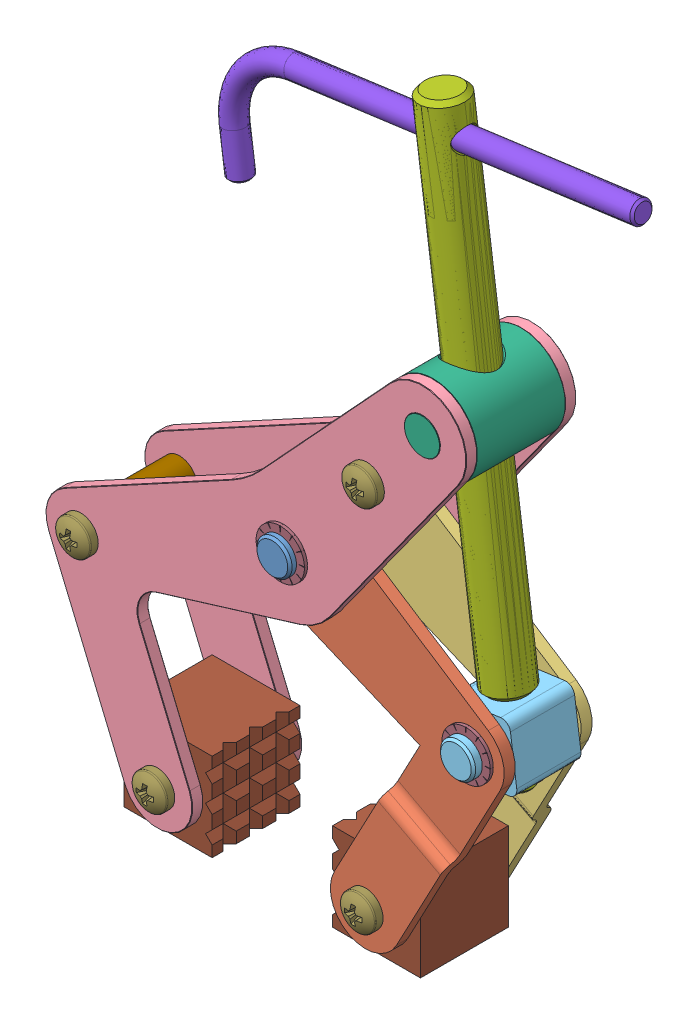
SolidWorks assembly Manual Clamp Assembly, configuration Default. Lengths in mm.
Overall size (140.09 169.84 31.04).
28 component instances, 13 part files, 60 mates.
Components (placement in the parent):
- Clamp hinge-1: Clamp hinge [Default] at origin size (18 18 30)
- Clamp elbow left-1: Clamp elbow left [Default] at (52.873 3.6662 7.5) x (0.468304 0.883567 0) z (0.883567 -0.468304 0) size (65 5 65)
- Clamp elbow right-1: Clamp elbow right [Default] at (43.507 -14.0051 -7.5) x (-0.468304 -0.883567 0) z (0.883567 -0.468304 0) size (65 5 65)
- Clamp Base-1: Clamp Base [Default] at (0 0 11.25) x (-0.598314 0.801262 0) z (-0.801262 -0.598314 0) size (61.66 2.5 125.92)
- Clamp Base-2: Clamp Base [Default] at (0 0 -11.25) x (-0.598314 0.801262 0) z (-0.801262 -0.598314 0) size (61.66 2.5 125.92)
- Clamp Tee-1: Clamp Tee [Default] at (32.3288 -22.0835 0) x (0 0 -1) z (0.134644 -0.990894 0) size (26 15 14.6)
- Clamp base spacer-1: Clamp base spacer [Default] at (31.6358 38.7192 0) x (0.134644 -0.990894 0) z (0 0 1) size (20 20 25.2)
- Clamp Rod-1: Clamp Rod [Default] at (23.6975 97.14 0) x (0.990894 0.134644 0.000515) z (0.134644 -0.990894 0) size (10 10 130)
- Clamp Lever-1: Clamp Lever [Default] at (69.3648 95.2718 0.0232) x (0.990894 0.134644 0.000515) z (-0.00051 -0.000069 1) size (98.5 28.5 5)
- Clamp base support-1: Clamp base support [Default] at (18.9815 23.2315 0) x (0.067715 -0.997705 0) z (0 0 1) size (8 8 24)
- Clamp base support-2: Clamp base support [Default] at (-46.1103 -19.3349 0) x (-0.069382 0.99759 0) z (0 0 1) size (8 8 24)
- Clamp Foot Pin-1: Clamp Foot Pin [Default] at (18.6868 -60.8342 0) x (0.923896 -0.382643 0) z (0 0 1) size (6 6 25)
- Clamp Foot Pin-2: Clamp Foot Pin [Default] at (-28.7088 -60.8342 0) x (0.923896 -0.382643 0) z (0 0 1) size (6 6 25)
- Clamp Foot-1: Clamp Foot [Default] at (28.6868 -60.8342 0) x (0 1 0) z (0 0 1) size (20 20 20)
- Clamp Foot-2: Clamp Foot [Default] at (-38.7088 -60.8342 0) x (0 1 0) z (0 0 -1) size (20 20 20)
- pan head cross recess screw_iso-2: pan head cross recess screw_iso [ISO 7045 - M4 x 10 - Z - 10N] at (-46.1103 -19.3349 15.6) x (0 0 -1) z (1 0 0) size (13.02 8 8)
- pan head cross recess screw_iso-3: pan head cross recess screw_iso [ISO 7045 - M4 x 10 - Z - 10N] at (-28.7088 -60.8342 15.6) x (0 0 -1) z (1 0 0) size (13.02 8 8)
- pan head cross recess screw_iso-4: pan head cross recess screw_iso [ISO 7045 - M4 x 10 - Z - 10N] at (18.6868 -60.8342 15.6) x (0 0 -1) z (1 0 0) size (13.02 8 8)
- pan head cross recess screw_iso-5: pan head cross recess screw_iso [ISO 7045 - M4 x 10 - Z - 10N] at (18.9815 23.2315 15.6) x (0 0 -1) z (1 0 0) size (13.02 8 8)
- pan head cross recess screw_iso-6: pan head cross recess screw_iso [ISO 7045 - M4 x 10 - Z - 10N] at (18.6868 -60.8342 -15.6) x (0 0 1) z (-1 0 0) size (13.02 8 8)
- pan head cross recess screw_iso-7: pan head cross recess screw_iso [ISO 7045 - M4 x 10 - Z - 10N] at (-28.7088 -60.8342 -15.6) x (0 0 1) z (-1 0 0) size (13.02 8 8)
- pan head cross recess screw_iso-8: pan head cross recess screw_iso [ISO 7045 - M4 x 10 - Z - 10N] at (-46.1103 -19.3349 -15.6) x (0 0 1) z (-1 0 0) size (13.02 8 8)
- pan head cross recess screw_iso-9: pan head cross recess screw_iso [ISO 7045 - M4 x 10 - Z - 10N] at (18.9815 23.2315 -15.6) x (0 0 1) z (-1 0 0) size (13.02 8 8)
- serrated lock washer 1_din-3: serrated lock washer 1_din [DIN 6798-A6.4] at (0 0 12.5) x (0 0 1) z (-1 0 0) size (0.7 11 11)
- serrated lock washer 1_din-5: serrated lock washer 1_din [DIN 6798-A6.4] at (0 0 -12.5) x (0 0 -1) z (1 0 0) size (0.7 11 11)
- serrated lock washer 1_din-6: serrated lock washer 1_din [DIN 6798-A6.4] at (39.7605 -21.0737 -10) x (0 0 -1) z (1 0 0) size (0.7 11 11)
- serrated lock washer 1_din-7: serrated lock washer 1_din [DIN 6798-A6.4] at (39.7605 -21.0737 10) x (0 0 1) z (-1 0 0) size (0.7 11 11)
- serrated lock washer 1_din-8: serrated lock washer 1_din [DIN 6798-A5.3] at (40.7973 -28.7036 0) x (0.134644 -0.990894 0) z (0 0 1) size (0.6 10 10)
Mates (geometry in assembly coordinates):
- Concentric1: concentric anti-aligned: cylinder of Clamp hinge-1 through (0 0 15) axis (0 0 -1) radius 4; cylinder of Clamp elbow left-1 through (0 0 7.5) axis (0 0 1) radius 4
- Coincident2: coincident anti-aligned: plane of Clamp hinge-1 through (0 0 7.5) normal (0 0 1); plane of Clamp elbow left-1 through (50.5755 -17.7516 7.5) normal (0 0 -1)
- Coincident3: coincident anti-aligned: plane of Clamp hinge-1 through (0 0 -7.5) normal (0 0 -1); plane of Clamp elbow right-1 through (50.5755 -17.7516 -7.5) normal (0 0 1)
- Concentric2: concentric anti-aligned: cylinder of Clamp hinge-1 through (0 0 -15) axis (0 0 1) radius 4; cylinder of Clamp elbow right-1 through (0 0 -7.5) axis (0 0 -1) radius 4
- Coincident4: coincident aligned: plane of Clamp elbow left-1 through (6.5399 10.0613 7.5) normal (0.54499 0.838443 0); plane of Clamp elbow right-1 through (6.5399 10.0613 -7.5) normal (0.54499 0.838443 0)
- Concentric3: concentric anti-aligned: cylinder of Clamp hinge-1 through (0 0 15) axis (0 0 -1) radius 4; cylinder of Clamp Base-1 through (0 0 10) axis (0 0 1) radius 4
- Coincident5: coincident anti-aligned: plane of Clamp elbow left-1 through (36.8776 -43.5959 10) normal (0 0 1); plane of Clamp Base-1 through (-27.2143 -28.1947 10) normal (0 0 -1)
- Concentric4: concentric aligned: cylinder of Clamp hinge-1 through (0 0 -15) axis (0 0 1) radius 4; cylinder of Clamp Base-2 through (0 0 -12.5) axis (0 0 1) radius 4
- Coincident6: coincident anti-aligned: plane of Clamp elbow right-1 through (36.8776 -43.5959 -10) normal (0 0 -1); plane of Clamp Base-2 through (-27.2143 -28.1947 -10) normal (0 0 1)
- Coincident7: coincident aligned: plane of Clamp Base-1 through (-11.8818 8.3428 10) normal (-0.476981 0.878914 0); plane of Clamp Base-2 through (-11.8818 8.3428 -12.5) normal (-0.476981 0.878914 0)
- Concentric5: concentric anti-aligned: cylinder of Clamp elbow left-1 through (39.7605 -21.0737 7.5) axis (0 0 1) radius 4; cylinder of Clamp Tee-1 through (39.7605 -21.0737 13) axis (0 0 -1) radius 4
- Concentric6: concentric anti-aligned: cylinder of Clamp Base-1 through (31.6358 38.7192 10) axis (0 0 1) radius 4; cylinder of Clamp base spacer-1 through (31.6358 38.7192 12.6) axis (0 0 -1) radius 4
- Concentric7: concentric aligned: cylinder of Clamp Tee-1 through (40.7434 -28.3072 0) axis (-0.134644 0.990894 0) radius 3; cylinder of Clamp Rod-1 through (41.2012 -31.6763 0) axis (-0.134644 0.990894 0) radius 3
- Coincident10: coincident anti-aligned: plane of Clamp Tee-1 through (46.2093 -12.8303 -7.3) normal (-0.134644 0.990894 0); plane of Clamp Rod-1 through (38.7776 -13.8402 0) normal (0.134644 -0.990894 0)
- Concentric9: concentric anti-aligned: cylinder of Clamp base spacer-1 through (30.2893 48.6282 0) axis (0.134644 -0.990894 0) radius 5; cylinder of Clamp Rod-1 through (38.7776 -13.8402 0) axis (-0.134644 0.990894 0) radius 5
- Concentric10: concentric anti-aligned: cylinder of Clamp Rod-1 through (19.8202 88.5396 -0.0026) axis (0.990894 0.134644 0.000515) radius 2.5; cylinder of Clamp Lever-1 through (69.3648 95.2718 0.0232) axis (-0.990894 -0.134644 -0.000515) radius 2.5
- Distance1: distance = 45 mm aligned: plane of Clamp Lever-1 through (69.3648 95.2718 0.0232) normal (0.990894 0.134644 0.000515); plane of Clamp Rod-1 through (23.6975 97.14 0) normal (0.990894 0.134644 0.000515)
- Parallel2: parallel anti-aligned: plane of Clamp Rod-1 through (23.6975 97.14 0) normal (-0.134644 0.990894 0); plane of Clamp Lever-1 through (-22.2602 56.5827 -0.0262) normal (0.134644 -0.990894 0)
- Concentric11: concentric aligned: cylinder of Clamp Base-2 through (18.9815 23.2315 -12.5) axis (0 0 1) radius 3; cylinder of Clamp base support-1 through (18.9815 23.2315 -12) axis (0 0 1) radius 3
- Coincident13: coincident anti-aligned: plane of Clamp Base-2 through (-27.2143 -28.1947 -10) normal (0 0 1); plane of Clamp base support-1 through (18.9815 23.2315 -10) normal (0 0 -1)
- Concentric12: concentric anti-aligned: cylinder of Clamp Base-1 through (-46.1103 -19.3349 10) axis (0 0 1) radius 3; cylinder of Clamp base support-2 through (-46.1103 -19.3349 12) axis (0 0 -1) radius 3
- Coincident14: coincident anti-aligned: plane of Clamp Base-1 through (-27.2143 -28.1947 10) normal (0 0 -1); plane of Clamp base support-2 through (-46.1103 -19.3349 10) normal (0 0 1)
- Concentric13: concentric anti-aligned: cylinder of Clamp elbow left-1 through (18.6868 -60.8342 7.5) axis (0 0 1) radius 3; cylinder of Clamp Foot Pin-1 through (18.6868 -60.8342 12.5) axis (0 0 -1) radius 3
- Coincident16: coincident aligned: plane of Clamp elbow left-1 through (22.0089 -71.6492 12.5) normal (0 0 1); plane of Clamp Foot Pin-1 through (18.6868 -60.8342 12.5) normal (0 0 1)
- Coincident18: coincident aligned: plane of Clamp elbow left-1 through (36.8776 -43.5959 10) normal (0 0 1); plane of Clamp Tee-1 through (44.4953 -20.4303 10) normal (0 0 1)
- Concentric14: concentric anti-aligned: cylinder of Clamp Base-1 through (-28.7088 -60.8342 10) axis (0 0 1) radius 3; cylinder of Clamp Foot Pin-2 through (-28.7088 -60.8342 12.5) axis (0 0 -1) radius 3
- Coincident19: coincident aligned: plane of Clamp Base-1 through (-27.2143 -28.1947 12.5) normal (0 0 1); plane of Clamp Foot Pin-2 through (-28.7088 -60.8342 12.5) normal (0 0 1)
- Concentric15: concentric anti-aligned: cylinder of Clamp Foot Pin-1 through (18.6868 -60.8342 12.5) axis (0 0 -1) radius 3; cylinder of Clamp Foot-1 through (18.6868 -60.8342 -10) axis (0 0 1) radius 3
- Coincident20: coincident anti-aligned: plane of Clamp elbow left-1 through (35.7068 -45.8048 10) normal (0 0 -1); plane of Clamp Foot-1 through (8.6868 -50.8342 10) normal (0 0 1)
- Concentric16: concentric aligned: cylinder of Clamp Foot Pin-2 through (-28.7088 -60.8342 12.5) axis (0 0 -1) radius 3; cylinder of Clamp Foot-2 through (-28.7088 -60.8342 10) axis (0 0 -1) radius 3
- Coincident21: coincident anti-aligned: plane of Clamp Base-1 through (-27.2143 -28.1947 10) normal (0 0 -1); plane of Clamp Foot-2 through (-18.7088 -50.8342 10) normal (0 0 1)
- Parallel4: parallel anti-aligned: plane of Clamp Foot-2 through (-18.7088 -70.8342 -10) normal (0 -1 0)
- Parallel5: parallel anti-aligned: plane of Clamp Foot-2 through (-18.7088 -70.8342 -10) normal (0 -1 0)
- Coincident25: coincident aligned: plane of Clamp Foot-1 through (8.6868 -70.8342 10) normal (0 -1 0); plane of Clamp Foot-2 through (-18.7088 -70.8342 -10) normal (0 -1 0)
- Concentric17: concentric anti-aligned: cone of Clamp Base-1 through (-46.1103 -19.3349 12.5) axis (0 0 -1); cylinder of pan head cross recess screw_iso-2 through (-46.1103 -19.3349 41) axis (0 0 1) radius 4
- Coincident26: coincident anti-aligned: plane of Clamp Base-1 through (-27.2143 -28.1947 12.5) normal (0 0 1); plane of pan head cross recess screw_iso-2 through (-46.1103 -17.3349 12.5) normal (0 0 -1)
- Concentric18: concentric anti-aligned: cone of Clamp Base-1 through (-28.7088 -60.8342 12.5) axis (0 0 -1); cylinder of pan head cross recess screw_iso-3 through (-28.7088 -60.8342 41) axis (0 0 1) radius 4
- Coincident27: coincident anti-aligned: plane of Clamp Base-1 through (-27.2143 -28.1947 12.5) normal (0 0 1); plane of pan head cross recess screw_iso-3 through (-28.7088 -58.8342 12.5) normal (0 0 -1)
- Concentric19: concentric anti-aligned: cylinder of Clamp elbow left-1 through (18.6868 -60.8342 7.5) axis (0 0 -1) radius 8; cylinder of pan head cross recess screw_iso-4 through (18.6868 -60.8342 41) axis (0 0 1) radius 4
- Coincident28: coincident anti-aligned: plane of Clamp elbow left-1 through (22.0089 -71.6492 12.5) normal (0 0 1); plane of pan head cross recess screw_iso-4 through (18.6868 -58.8342 12.5) normal (0 0 -1)
- Concentric20: concentric anti-aligned: cone of Clamp Base-1 through (18.9815 23.2315 12.5) axis (0 0 -1); cylinder of pan head cross recess screw_iso-5 through (18.9815 23.2315 41) axis (0 0 1) radius 4
- Coincident29: coincident anti-aligned: plane of Clamp Base-1 through (-27.2143 -28.1947 12.5) normal (0 0 1); plane of pan head cross recess screw_iso-5 through (18.9815 25.2315 12.5) normal (0 0 -1)
- Concentric21: concentric anti-aligned: cylinder of Clamp elbow right-1 through (18.6868 -60.8342 -7.5) axis (0 0 1) radius 8; cylinder of pan head cross recess screw_iso-6 through (18.6868 -60.8342 -41) axis (0 0 -1) radius 4
- Coincident30: coincident anti-aligned: plane of Clamp elbow right-1 through (22.0089 -71.6492 -12.5) normal (0 0 -1); plane of pan head cross recess screw_iso-6 through (18.6868 -58.8342 -12.5) normal (0 0 1)
- Concentric22: concentric aligned: cone of Clamp Base-2 through (-28.7088 -60.8342 -12.5) axis (0 0 -1); cylinder of pan head cross recess screw_iso-7 through (-28.7088 -60.8342 -41) axis (0 0 -1) radius 4
- Coincident31: coincident anti-aligned: plane of Clamp Base-2 through (-27.2143 -28.1947 -12.5) normal (0 0 -1); plane of pan head cross recess screw_iso-7 through (-28.7088 -58.8342 -12.5) normal (0 0 1)
- Concentric23: concentric anti-aligned: cone of Clamp Base-2 through (-46.1103 -19.3349 -12.4) axis (0 0 1); cylinder of pan head cross recess screw_iso-8 through (-46.1103 -19.3349 -41) axis (0 0 -1) radius 4
- Coincident32: coincident anti-aligned: plane of Clamp Base-2 through (-27.2143 -28.1947 -12.5) normal (0 0 -1); plane of pan head cross recess screw_iso-8 through (-46.1103 -17.3349 -12.5) normal (0 0 1)
- Concentric24: concentric anti-aligned: cone of Clamp Base-2 through (18.9815 23.2315 -12.4) axis (0 0 1); cylinder of pan head cross recess screw_iso-9 through (18.9815 23.2315 -41) axis (0 0 -1) radius 4
- Coincident33: coincident anti-aligned: plane of Clamp Base-2 through (-27.2143 -28.1947 -12.5) normal (0 0 -1); plane of pan head cross recess screw_iso-9 through (18.9815 25.2315 -12.5) normal (0 0 1)
- Concentric26: concentric anti-aligned: cylinder of Clamp hinge-1 through (0 0 15) axis (0 0 1) radius 3; cylinder of serrated lock washer 1_din-3 through (0 0 13.2) axis (0 0 -1) radius 5.5
- Coincident35: coincident anti-aligned: plane of Clamp hinge-1 through (0 4.614 12.5) normal (0 0 1); plane of serrated lock washer 1_din-3 through (0 0 12.5) normal (0 0 -1)
- Concentric28: concentric anti-aligned: cylinder of Clamp hinge-1 through (0 0 -15) axis (0 0 -1) radius 3; cylinder of serrated lock washer 1_din-5 through (0 0 -13.2) axis (0 0 1) radius 5.5
- Coincident37: coincident anti-aligned: plane of Clamp hinge-1 through (0 4.614 -12.5) normal (0 0 -1); plane of serrated lock washer 1_din-5 through (0 0 -12.5) normal (0 0 1)
- Concentric29: concentric anti-aligned: cylinder of Clamp elbow right-1 through (39.7605 -21.0737 -7.5) axis (0 0 -1) radius 4; cylinder of serrated lock washer 1_din-6 through (39.7605 -21.0737 -10.7) axis (0 0 1) radius 5.5
- Coincident38: coincident anti-aligned: plane of Clamp elbow right-1 through (36.8776 -43.5959 -10) normal (0 0 -1); plane of serrated lock washer 1_din-6 through (39.7605 -21.0737 -10) normal (0 0 1)
- Concentric301: concentric anti-aligned: cylinder of Clamp elbow left-1 through (39.7605 -21.0737 7.5) axis (0 0 1) radius 4; cylinder of serrated lock washer 1_din-7 through (39.7605 -21.0737 10.7) axis (0 0 -1) radius 5.5
- Coincident391: coincident anti-aligned: plane of Clamp elbow left-1 through (36.8776 -43.5959 10) normal (0 0 1); plane of serrated lock washer 1_din-7 through (39.7605 -21.0737 10) normal (0 0 -1)
- Concentric31: concentric anti-aligned: cylinder of Clamp Rod-1 through (41.2012 -31.6763 0) axis (0.134644 -0.990894 0) radius 2.5; cylinder of serrated lock washer 1_din-8 through (40.8781 -29.2981 0) axis (-0.134644 0.990894 0) radius 5
- Coincident40: coincident anti-aligned: plane of Clamp Rod-1 through (40.7949 -28.7039 4.6596) normal (0.134644 -0.990894 0); plane of serrated lock washer 1_din-8 through (40.7973 -28.7036 0) normal (-0.134644 0.990894 0)
